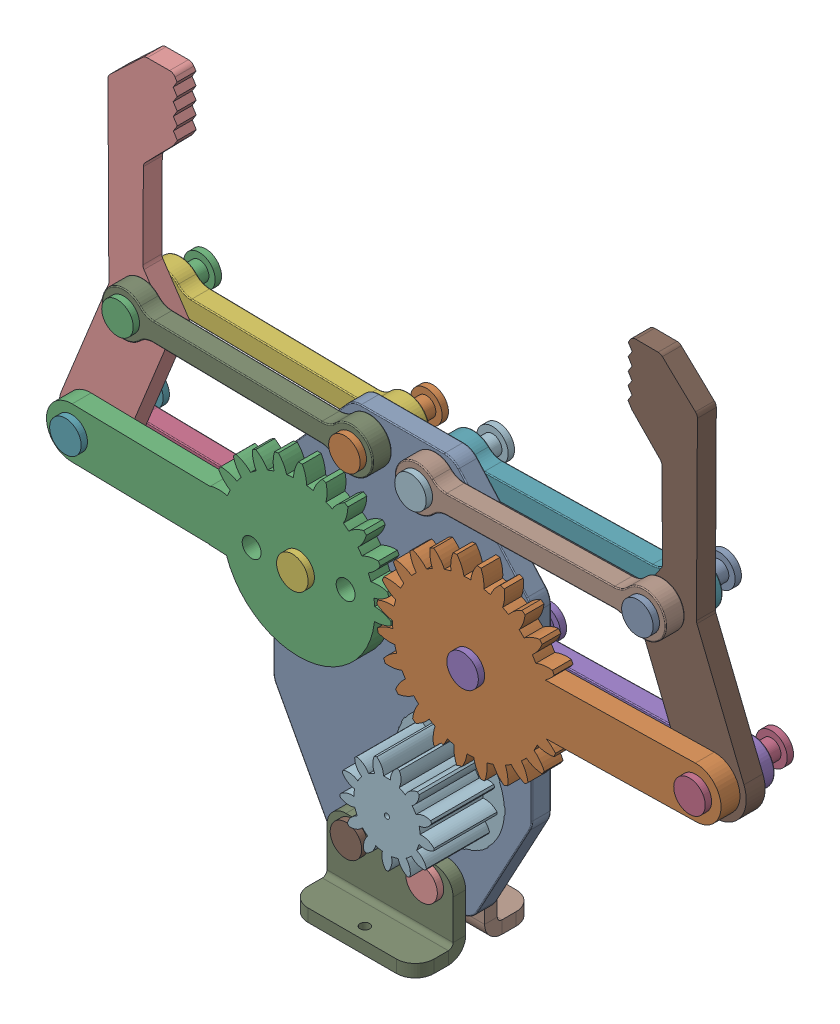
SolidWorks assembly Gripper Assem, configuration Default. Lengths in mm.
Overall size (131.93 100.78 21).
24 component instances, 8 part files, 82 mates.
Components (placement in the parent):
- Part3-3-1: Part3-3 [Default] at origin size (41 62 3)
- part4-4-1: part4-4 [Default] at (13.5 37.5997 3) x (0 0 1) z (-0.999794 -0.020285 0) size (3 29.07 54.54)
- part5-5-1: part5-5 [Default] at (-13.5 37.5997 6) x (0 0 -1) z (0.993667 0.112368 0) size (3 26.63 54.23)
- Part2-2-1: Part2-2 [Default] at (-13.5 37.5997 -1.5) x (-0.999833 0.018293 0) z (0 0 1) size (43 7 3)
- Part2-2-2: Part2-2 [Default] at (49.4926 38.33 -1.5) x (-0.999794 -0.020285 0) z (0 0 1) size (43 7 3)
- Part2-2-3: Part2-2 [Default] at (-41.234 58.6488 -1.5) x (0.999838 -0.018022 0) z (0 0 1) size (43 7 3)
- Part2-2-4: Part2-2 [Default] at (41.2326 58.7205 -1.5) x (-0.9998 -0.020013 0) z (0 0 1) size (43 7 3)
- Part2-2-5: Part2-2 [Default] at (41.2326 58.7205 4.5) x (-0.9998 -0.020013 0) z (0 0 1) size (43 7 3)
- Part2-2-6: Part2-2 [Default] at (-41.234 58.6488 4.5) x (0.999838 -0.018022 0) z (0 0 1) size (43 7 3)
- Part1-1-2: Part1-1 [Default] at (-49.494 38.2583 0) x (0.375454 0.926841 0) z (0 0 1) size (60.3 20.75 3)
- Part1-1-4: Part1-1 [Default] at (49.4926 38.33 3) x (-0.375454 0.926841 0) z (0 0 -1) size (60.3 20.75 3)
- Part6-6-3: Part6-6 [Default] at (5.2398 58 -7) x (0 1 0) z (1 0 0) size (5 14 5)
- Part6-6-4: Part6-6 [Default] at (41.2326 58.7205 -7) x (0.650948 0.759122 0) z (0.759122 -0.650948 0) size (5 14 5)
- Part6-6-5: Part6-6 [Default] at (-5.2398 58 -7) x (0.014078 0.999901 0) z (0.999901 -0.014078 0) size (5 14 5)
- Part6-6-6: Part6-6 [Default] at (-41.234 58.6488 -7) x (0.832834 0.553523 0) z (0.553523 -0.832834 0) size (5 14 5)
- Part6-6-7: Part6-6 [Default] at (49.4926 38.33 -7) x (0.014078 0.999901 0) z (0.999901 -0.014078 0) size (5 14 5)
- Part6-6-8: Part6-6 [Default] at (13.5 37.5997 -7) x (0.014078 0.999901 0) z (0.999901 -0.014078 0) size (5 14 5)
- Part6-6-9: Part6-6 [Default] at (-13.5 37.5997 -7) x (0.723192 -0.690647 0) z (-0.690647 -0.723192 0) size (5 14 5)
- Part6-6-10: Part6-6 [Default] at (-49.494 38.2583 -7) x (0.832834 0.553523 0) z (0.553523 -0.832834 0) size (5 14 5)
- Part7-7-1: Part7-7 [Default] at (0 -5.279 0) x (0 -1 0) z (1 0 0) size (12 8 20)
- Part7-7-2: Part7-7 [Default] at (0 -5.279 3) x (0 -1 0) z (-1 0 0) size (12 8 20)
- Part6-6-11: Part6-6 [Default] at (6 4 -8) x (-1 0 0) z (0 1 0) size (5 14 5)
- Part6-6-12: Part6-6 [Default] at (-6 4 -8) x (-1 0 0) z (0 1 0) size (5 14 5)
- part8-8-1: part8-8 [Default] at (7.5 17.5997 13) x (0 0 -1) z (1 0 0) size (13 17.5 17.5)
Mates (geometry in assembly coordinates):
- Coincident3: coordinate: point of Part3-3-1
- Concentric1: concentric aligned: cylinder of Part3-3-1 through (13.5 37.5997 3) axis (0 0 -1) radius 1.5; cylinder of part4-4-1 through (13.5 37.5997 53.0001) axis (0 0 -1) radius 1.5
- Coincident4: coincident anti-aligned: plane of Part3-3-1 through (0 0 3) normal (0 0 1); plane of part4-4-1 through (13.5 37.5997 3) normal (0 0 -1)
- Concentric3: concentric anti-aligned: cylinder of Part3-3-1 through (-13.5 37.5997 3) axis (0 0 -1) radius 1.5; cylinder of part5-5-1 through (-13.5 37.5997 -44.0001) axis (0 0 1) radius 1.5
- Coincident6: coincident anti-aligned: plane of Part3-3-1 through (0 0 3) normal (0 0 1); plane of part5-5-1 through (-13.5 37.5997 3) normal (0 0 -1)
- GearMate4: gear = 10.8 : 10.8 mm: cylinder of part5-5-1 through (-1.6685 33.0229 3) axis (0 0 1) radius 5.4; cylinder of part4-4-1 through (2.1408 43.2477 6) axis (0 0 -1) radius 5.4
- Concentric4: concentric aligned: cylinder of Part3-3-1 through (-13.5 37.5997 3) axis (0 0 -1) radius 1.5; cylinder of Part2-2-1 through (-13.5 37.5997 0) axis (0 0 -1) radius 1.5
- Coincident7: coincident anti-aligned: plane of Part3-3-1 through (0 0 0) normal (0 0 -1); plane of Part2-2-1 through (-13.5 37.5997 0) normal (0 0 1)
- Concentric8: concentric aligned: cylinder of Part3-3-1 through (-5.2398 58 3) axis (0 0 -1) radius 1.5; cylinder of Part2-2-6 through (-5.2398 58 6) axis (0 0 -1) radius 1.5
- Coincident11: coincident anti-aligned: plane of Part3-3-1 through (0 0 3) normal (0 0 1); plane of Part2-2-6 through (-41.234 58.6488 3) normal (0 0 -1)
- Concentric9: concentric aligned: cylinder of Part3-3-1 through (5.2398 58 3) axis (0 0 -1) radius 1.5; cylinder of Part2-2-5 through (5.2398 58 6) axis (0 0 -1) radius 1.5
- Coincident12: coincident anti-aligned: plane of Part3-3-1 through (0 0 3) normal (0 0 1); plane of Part2-2-5 through (41.2326 58.7205 3) normal (0 0 -1)
- Concentric6: concentric aligned: cylinder of Part3-3-1 through (-5.2398 58 3) axis (0 0 -1) radius 1.5; cylinder of Part2-2-3 through (-5.2398 58 0) axis (0 0 -1) radius 1.5
- Coincident9: coincident anti-aligned: plane of Part3-3-1 through (0 0 0) normal (0 0 -1); plane of Part2-2-3 through (-41.234 58.6488 0) normal (0 0 1)
- Concentric7: concentric aligned: cylinder of Part3-3-1 through (5.2398 58 3) axis (0 0 -1) radius 1.5; cylinder of Part2-2-4 through (5.2398 58 0) axis (0 0 -1) radius 1.5
- Coincident10: coincident anti-aligned: plane of Part3-3-1 through (0 0 0) normal (0 0 -1); plane of Part2-2-4 through (41.2326 58.7205 0) normal (0 0 1)
- Concentric5: concentric aligned: cylinder of Part3-3-1 through (13.5 37.5997 3) axis (0 0 -1) radius 1.5; cylinder of Part2-2-2 through (13.5 37.5997 0) axis (0 0 -1) radius 1.5
- Coincident8: coincident anti-aligned: plane of Part3-3-1 through (0 0 0) normal (0 0 -1); plane of Part2-2-2 through (49.4926 38.33 0) normal (0 0 1)
- Concentric45: concentric anti-aligned: cylinder of part5-5-1 through (-49.494 38.2583 3) axis (0 0 1) radius 1.5; cylinder of Part1-1-2 through (-49.494 38.2583 3) axis (0 0 -1) radius 1.5
- Concentric46: concentric aligned: cylinder of Part2-2-1 through (-49.494 38.2583 0) axis (0 0 -1) radius 1.5; cylinder of Part1-1-2 through (-49.494 38.2583 3) axis (0 0 -1) radius 1.5
- Coincident17: coincident anti-aligned: plane of Part2-2-1 through (-13.5 37.5997 0) normal (0 0 1); plane of Part1-1-2 through (-49.494 38.2583 0) normal (0 0 -1)
- Coincident18: coincident anti-aligned: plane of part5-5-1 through (-13.5 37.5997 3) normal (0 0 -1); plane of Part1-1-2 through (-49.494 38.2583 3) normal (0 0 1)
- Concentric47: concentric aligned: cylinder of Part2-2-3 through (-41.234 58.6488 0) axis (0 0 -1) radius 1.5; cylinder of Part1-1-2 through (-41.234 58.6488 3) axis (0 0 -1) radius 1.5
- Concentric48: concentric aligned: cylinder of Part2-2-6 through (-41.234 58.6488 6) axis (0 0 -1) radius 1.5; cylinder of Part1-1-2 through (-41.234 58.6488 3) axis (0 0 -1) radius 1.5
- Coincident19: coincident anti-aligned: plane of Part2-2-6 through (-41.234 58.6488 3) normal (0 0 -1); plane of Part1-1-2 through (-49.494 38.2583 3) normal (0 0 1)
- Coincident20: coincident anti-aligned: plane of Part2-2-3 through (-41.234 58.6488 0) normal (0 0 1); plane of Part1-1-2 through (-49.494 38.2583 0) normal (0 0 -1)
- Concentric51: concentric anti-aligned: cylinder of part4-4-1 through (49.4926 38.33 6) axis (0 0 -1) radius 1.5; cylinder of Part1-1-4 through (49.4926 38.33 0) axis (0 0 1) radius 1.5
- Concentric52: concentric anti-aligned: cylinder of Part2-2-2 through (49.4926 38.33 0) axis (0 0 -1) radius 1.5; cylinder of Part1-1-4 through (49.4926 38.33 0) axis (0 0 1) radius 1.5
- Coincident23: coincident anti-aligned: plane of part4-4-1 through (13.5 37.5997 3) normal (0 0 -1); plane of Part1-1-4 through (49.4926 38.33 3) normal (0 0 1)
- Coincident24: coincident anti-aligned: plane of Part2-2-2 through (49.4926 38.33 0) normal (0 0 1); plane of Part1-1-4 through (49.4926 38.33 0) normal (0 0 -1)
- Concentric53: concentric anti-aligned: cylinder of Part2-2-5 through (41.2326 58.7205 6) axis (0 0 -1) radius 1.5; cylinder of Part1-1-4 through (41.2326 58.7205 0) axis (0 0 1) radius 1.5
- Concentric54: concentric anti-aligned: cylinder of Part2-2-4 through (41.2326 58.7205 0) axis (0 0 -1) radius 1.5; cylinder of Part1-1-4 through (41.2326 58.7205 0) axis (0 0 1) radius 1.5
- Coincident25: coincident anti-aligned: plane of Part2-2-4 through (41.2326 58.7205 0) normal (0 0 1); plane of Part1-1-4 through (49.4926 38.33 0) normal (0 0 -1)
- Coincident26: coincident anti-aligned: plane of Part2-2-5 through (41.2326 58.7205 3) normal (0 0 -1); plane of Part1-1-4 through (49.4926 38.33 3) normal (0 0 1)
- Concentric55: concentric anti-aligned: cylinder of Part1-1-4 through (41.2326 58.7205 0) axis (0 0 1) radius 1.5; cylinder of Part6-6-4 through (41.2326 58.7205 -7) axis (0 0 -1) radius 1.5
- Concentric56: concentric aligned: cylinder of Part2-2-5 through (41.2326 58.7205 6) axis (0 0 -1) radius 1.5; cylinder of Part6-6-4 through (41.2326 58.7205 -7) axis (0 0 -1) radius 1.5
- Concentric57: concentric aligned: cylinder of Part2-2-4 through (41.2326 58.7205 0) axis (0 0 -1) radius 1.5; cylinder of Part6-6-4 through (41.2326 58.7205 -7) axis (0 0 -1) radius 1.5
- Coincident27: coincident anti-aligned: plane of Part2-2-5 through (41.2326 58.7205 6) normal (0 0 1); plane of Part6-6-4 through (39.6052 56.8227 6) normal (0 0 -1)
- Concentric58: concentric aligned: cylinder of Part3-3-1 through (5.2398 58 3) axis (0 0 -1) radius 1.5; cylinder of Part6-6-3 through (5.2398 58 -7) axis (0 0 -1) radius 1.5
- Concentric59: concentric aligned: cylinder of Part2-2-5 through (5.2398 58 6) axis (0 0 -1) radius 1.5; cylinder of Part6-6-3 through (5.2398 58 -7) axis (0 0 -1) radius 1.5
- Concentric60: concentric aligned: cylinder of Part2-2-4 through (5.2398 58 0) axis (0 0 -1) radius 1.5; cylinder of Part6-6-3 through (5.2398 58 -7) axis (0 0 -1) radius 1.5
- Coincident28: coincident anti-aligned: plane of Part2-2-5 through (41.2326 58.7205 6) normal (0 0 1); plane of Part6-6-3 through (5.2398 55.5 6) normal (0 0 -1)
- Concentric61: concentric aligned: cylinder of Part3-3-1 through (-5.2398 58 3) axis (0 0 -1) radius 1.5; cylinder of Part6-6-5 through (-5.2398 58 -7) axis (0 0 -1) radius 1.5
- Concentric62: concentric aligned: cylinder of Part2-2-6 through (-5.2398 58 6) axis (0 0 -1) radius 1.5; cylinder of Part6-6-5 through (-5.2398 58 -7) axis (0 0 -1) radius 1.5
- Concentric63: concentric aligned: cylinder of Part2-2-3 through (-5.2398 58 0) axis (0 0 -1) radius 1.5; cylinder of Part6-6-5 through (-5.2398 58 -7) axis (0 0 -1) radius 1.5
- Coincident29: coincident anti-aligned: plane of Part2-2-6 through (-41.234 58.6488 6) normal (0 0 1); plane of Part6-6-5 through (-5.275 55.5002 6) normal (0 0 -1)
- Concentric64: concentric aligned: cylinder of Part1-1-2 through (-41.234 58.6488 3) axis (0 0 -1) radius 1.5; cylinder of Part6-6-6 through (-41.234 58.6488 -7) axis (0 0 -1) radius 1.5
- Concentric65: concentric aligned: cylinder of Part2-2-3 through (-41.234 58.6488 0) axis (0 0 -1) radius 1.5; cylinder of Part6-6-6 through (-41.234 58.6488 -7) axis (0 0 -1) radius 1.5
- Concentric66: concentric aligned: cylinder of Part2-2-6 through (-41.234 58.6488 6) axis (0 0 -1) radius 1.5; cylinder of Part6-6-6 through (-41.234 58.6488 -7) axis (0 0 -1) radius 1.5
- Coincident30: coincident anti-aligned: plane of Part2-2-6 through (-41.234 58.6488 6) normal (0 0 1); plane of Part6-6-6 through (-43.3161 57.265 6) normal (0 0 -1)
- Concentric67: concentric anti-aligned: cylinder of Part1-1-4 through (49.4926 38.33 0) axis (0 0 1) radius 1.5; cylinder of Part6-6-7 through (49.4926 38.33 -7) axis (0 0 -1) radius 1.5
- Concentric68: concentric aligned: cylinder of Part2-2-2 through (49.4926 38.33 0) axis (0 0 -1) radius 1.5; cylinder of Part6-6-7 through (49.4926 38.33 -7) axis (0 0 -1) radius 1.5
- Concentric69: concentric aligned: cylinder of part4-4-1 through (49.4926 38.33 6) axis (0 0 -1) radius 1.5; cylinder of Part6-6-7 through (49.4926 38.33 -7) axis (0 0 -1) radius 1.5
- Coincident31: coincident anti-aligned: plane of part4-4-1 through (13.5 37.5997 6) normal (0 0 1); plane of Part6-6-7 through (49.4574 35.8302 6) normal (0 0 -1)
- Concentric70: concentric aligned: cylinder of Part3-3-1 through (13.5 37.5997 3) axis (0 0 -1) radius 1.5; cylinder of Part6-6-8 through (13.5 37.5997 -7) axis (0 0 -1) radius 1.5
- Concentric71: concentric aligned: cylinder of part4-4-1 through (13.5 37.5997 53.0001) axis (0 0 -1) radius 1.5; cylinder of Part6-6-8 through (13.5 37.5997 -7) axis (0 0 -1) radius 1.5
- Concentric72: concentric aligned: cylinder of Part2-2-2 through (13.5 37.5997 0) axis (0 0 -1) radius 1.5; cylinder of Part6-6-8 through (13.5 37.5997 -7) axis (0 0 -1) radius 1.5
- Coincident32: coincident anti-aligned: plane of part4-4-1 through (13.5 37.5997 6) normal (0 0 1); plane of Part6-6-8 through (13.4648 35.1 6) normal (0 0 -1)
- Concentric73: concentric aligned: cylinder of Part3-3-1 through (-13.5 37.5997 3) axis (0 0 -1) radius 1.5; cylinder of Part6-6-9 through (-13.5 37.5997 -7) axis (0 0 -1) radius 1.5
- Concentric74: concentric anti-aligned: cylinder of part5-5-1 through (-13.5 37.5997 -44.0001) axis (0 0 1) radius 1.5; cylinder of Part6-6-9 through (-13.5 37.5997 -7) axis (0 0 -1) radius 1.5
- Coincident33: coincident anti-aligned: plane of part5-5-1 through (-13.5 37.5997 6) normal (0 0 1); circle of Part6-6-9
- Concentric75: concentric aligned: cylinder of Part2-2-1 through (-13.5 37.5997 0) axis (0 0 -1) radius 1.5; cylinder of Part6-6-9 through (-13.5 37.5997 -7) axis (0 0 -1) radius 1.5
- Concentric76: concentric aligned: cylinder of Part1-1-2 through (-49.494 38.2583 3) axis (0 0 -1) radius 1.5; cylinder of Part6-6-10 through (-49.494 38.2583 -7) axis (0 0 -1) radius 1.5
- Concentric77: concentric aligned: cylinder of Part2-2-1 through (-49.494 38.2583 0) axis (0 0 -1) radius 1.5; cylinder of Part6-6-10 through (-49.494 38.2583 -7) axis (0 0 -1) radius 1.5
- Concentric78: concentric anti-aligned: cylinder of part5-5-1 through (-49.494 38.2583 3) axis (0 0 1) radius 1.5; cylinder of Part6-6-10 through (-49.494 38.2583 -7) axis (0 0 -1) radius 1.5
- Coincident34: coincident anti-aligned: plane of part5-5-1 through (-13.5 37.5997 6) normal (0 0 1); plane of Part6-6-10 through (-51.5761 36.8745 6) normal (0 0 -1)
- Concentric79: concentric aligned: cylinder of Part3-3-1 through (6 4 3) axis (0 0 -1) radius 1.5; cylinder of Part7-7-1 through (6 4 0) axis (0 0 -1) radius 1.5
- Concentric80: concentric aligned: cylinder of Part3-3-1 through (-6 4 3) axis (0 0 -1) radius 1.5; cylinder of Part7-7-1 through (-6 4 0) axis (0 0 -1) radius 1.5
- Coincident35: coincident anti-aligned: plane of Part3-3-1 through (0 0 0) normal (0 0 -1); plane of Part7-7-1 through (10 -5.279 0) normal (0 0 1)
- Concentric81: concentric anti-aligned: cylinder of Part3-3-1 through (6 4 3) axis (0 0 -1) radius 1.5; cylinder of Part7-7-2 through (6 4 3) axis (0 0 1) radius 1.5
- Concentric82: concentric anti-aligned: cylinder of Part3-3-1 through (-6 4 3) axis (0 0 -1) radius 1.5; cylinder of Part7-7-2 through (-6 4 3) axis (0 0 1) radius 1.5
- Coincident36: coincident anti-aligned: plane of Part3-3-1 through (0 0 3) normal (0 0 1); plane of Part7-7-2 through (-10 -5.279 3) normal (0 0 -1)
- Concentric83: concentric aligned: cylinder of Part3-3-1 through (6 4 3) axis (0 0 -1) radius 1.5; cylinder of Part6-6-11 through (6 4 -8) axis (0 0 -1) radius 1.5
- Concentric84: concentric anti-aligned: cylinder of Part7-7-2 through (6 4 3) axis (0 0 1) radius 1.5; cylinder of Part6-6-11 through (6 4 -8) axis (0 0 -1) radius 1.5
- Concentric85: concentric aligned: cylinder of Part7-7-1 through (6 4 0) axis (0 0 -1) radius 1.5; cylinder of Part6-6-11 through (6 4 -8) axis (0 0 -1) radius 1.5
- Coincident37: coincident anti-aligned: plane of Part7-7-2 through (-10 -5.279 5) normal (0 0 1); plane of Part6-6-11 through (8.5 4 5) normal (0 0 -1)
- Concentric86: concentric aligned: cylinder of Part3-3-1 through (-6 4 3) axis (0 0 -1) radius 1.5; cylinder of Part6-6-12 through (-6 4 -8) axis (0 0 -1) radius 1.5
- Concentric87: concentric anti-aligned: cylinder of Part7-7-2 through (-6 4 3) axis (0 0 1) radius 1.5; cylinder of Part6-6-12 through (-6 4 -8) axis (0 0 -1) radius 1.5
- Concentric88: concentric aligned: cylinder of Part7-7-1 through (-6 4 0) axis (0 0 -1) radius 1.5; cylinder of Part6-6-12 through (-6 4 -8) axis (0 0 -1) radius 1.5
- Coincident38: coincident anti-aligned: plane of Part7-7-2 through (-10 -5.279 5) normal (0 0 1); plane of Part6-6-12 through (-3.5 4 5) normal (0 0 -1)
- Concentric89: concentric aligned: circle of Part3-3-1; circle of part8-8-1
- Coincident39: coincident aligned: plane of Part3-3-1 through (0 0 0) normal (0 0 -1); plane of part8-8-1 through (7.5 17.5997 0) normal (0 0 -1)
